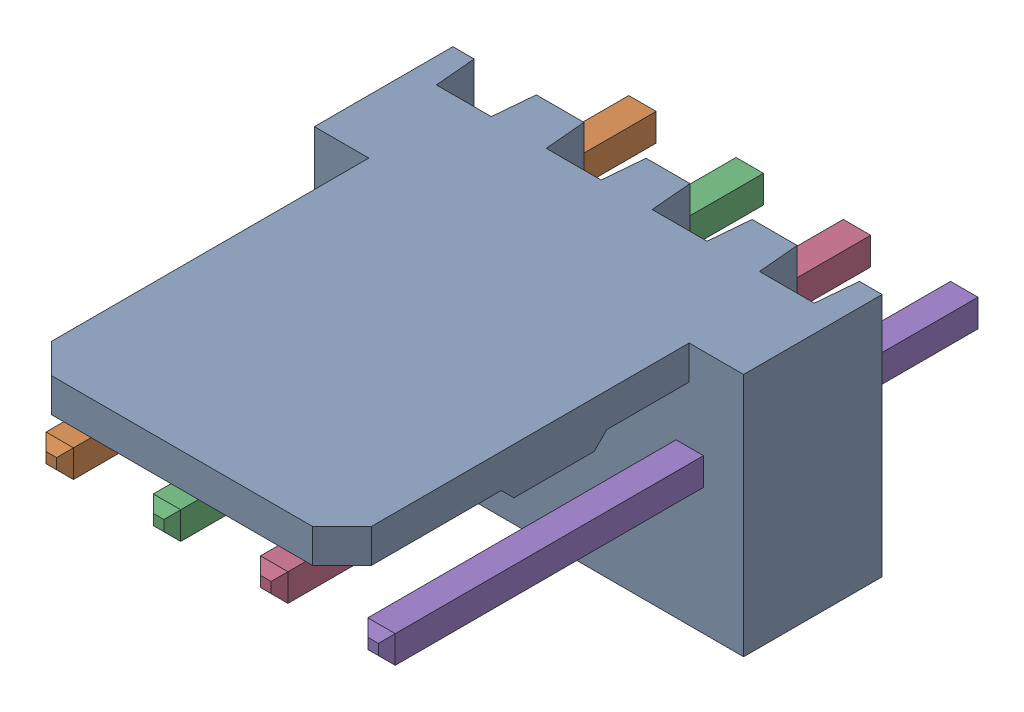
SolidWorks assembly Molex PCB 4 pin v3_4, configuration Predeterminado. Lengths in mm.
Overall size (10.16 5.79 14.92).
5 component instances, 2 part files, 0 mates.
Components (placement in the parent):
- BASE9710016-1: BASE9710016 [Predeterminado] at (2.54 2.895 -8.22) size (10.16 5.79 11.5)
- PINO9710016-1: PINO9710016 [Predeterminado] at (1.27 3.325 -0.72) size (0.65 0.65 14.2)
- PINO9710016-2: PINO9710016 [Predeterminado] at (3.81 3.325 -0.72) size (0.65 0.65 14.2)
- PINO9710016-3: PINO9710016 [Predeterminado] at (6.35 3.325 -0.72) size (0.65 0.65 14.2)
- PINO9710016-4: PINO9710016 [Predeterminado] at (8.89 3.325 -0.72) size (0.65 0.65 14.2)
